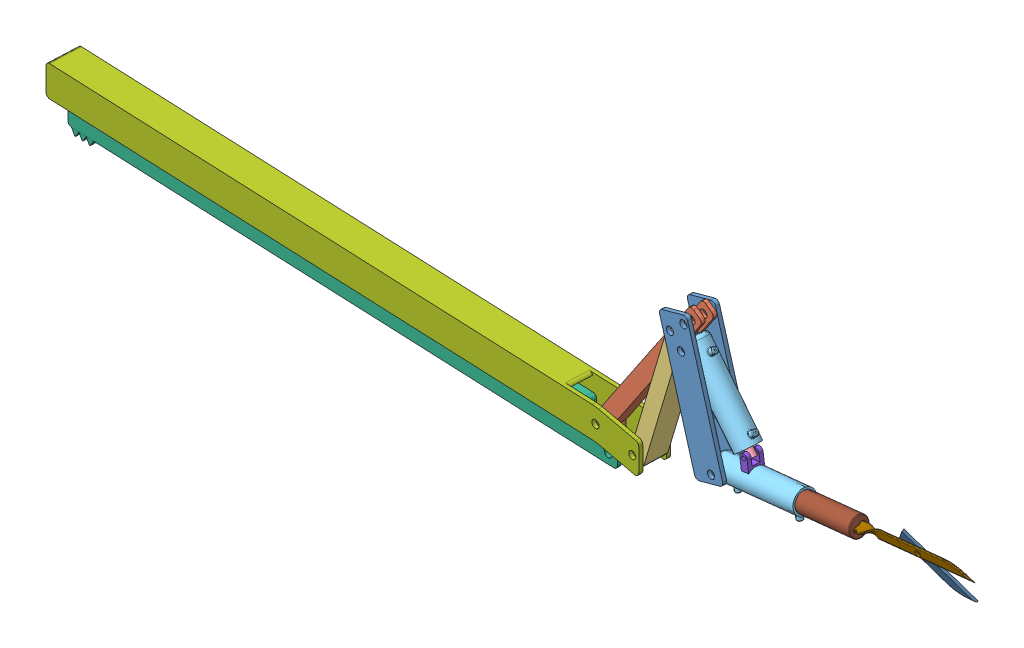
SolidWorks assembly robot arm, configuration Default. Lengths in mm.
Overall size (249.31 49.18 17.02).
13 component instances, 11 part files, 32 mates.
Components (placement in the parent):
- bottom arm-1: bottom arm [Default] at (-76.3272 70.555 28.6801) x (0.289518 -0.957095 0.01218) z (-0.042034 0 0.999116) size (35 8 8)
- mid arm1-1: mid arm1 [Default] at (-97.3359 34.2899 27.7962) x (-0.564195 -0.8253 -0.023736) z (0.042034 0 -0.999116) size (52.07 8.95 4)
- mid arm2-1: mid arm2 [Default] at (-87.409 30.4601 28.2139) x (0.293429 0.955901 0.012345) z (-0.042034 0 0.999116) size (39 4 6)
- piston-1: piston [Default] at (-71.6815 60.1738 28.8755) x (-0.649646 0.759745 -0.027331) z (-0.042034 0 0.999116) size (21 5 5)
- pump-1: pump [Default] at (-73.0366 61.7586 28.8185) x (0.649646 -0.759745 0.027331) z (-0.042034 0 0.999116) size (23 7.5 6)
- uper arm1-1: uper arm1 [Default] at (-93.5493 29.9098 27.9555) x (-0.999116 0 -0.042034) z (-0.042034 0 0.999116) size (150 11.53 4)
- uper arm2-1: uper arm2 [Default] at (-97.3359 34.4359 27.7962) x (-0.999116 0 -0.042034) z (-0.042034 0 0.999116) size (161.82 9.89 8)
- piston-2: piston [Default] at (-57.7397 40.4075 29.4621) x (-0.989211 -0.140461 -0.041617) z (-0.134091 0.982548 -0.128913) size (21 5 5)
- pump-2: pump [Default] at (-64.3331 39.4713 29.1847) x (0.989211 0.140461 0.041617) z (0.042034 0 -0.999116) size (23 7.5 6)
- fix plate-1: fix plate [Default] at (-58.838 44.0131 27.4141) x (0.989211 0.140461 0.041617) z (-0.042034 0 0.999116) size (2 9.44 6)
- sissors1-1: sissors1 [Default] at (-33.0095 43.919 30.5025) x (0.146102 -0.966743 -0.209912) z (-0.010748 -0.213728 0.976834) size (4.54 40 4.53)
- sissors2-1: sissors2 [Default] at (-17.9664 48.965 31.2602) x (-0.427031 -0.882348 -0.197753) z (0.904173 -0.419264 -0.081784) size (2.92 0.5 19.68)
- twist-1: twist [Default] at (-29.7107 44.3874 30.6413) x (-0.003755 0.308298 -0.951282) z (-0.146448 0.940863 0.3055) size (5 15 5)
Mates (geometry in assembly coordinates):
- 平行(R)1: parallel anti-aligned: plane of uper arm2-1 through (-247.3294 37.2899 24.4885) normal (0 -1 0); plane of assembly through (0 0 0) normal (0 1 0)
- 平行(R)2: parallel anti-aligned: plane of uper arm1-1 through (-243.5008 34.9098 23.6487) normal (0 1 0); plane of uper arm2-1 through (-247.3294 37.2899 24.4885) normal (0 -1 0)
- 重合/共線/共點11: coincident anti-aligned: plane of mid arm2-1 through (-74.1813 67.1529 31.773) normal (-0.042034 0 0.999116); plane of uper arm2-1 through (-247.3294 30.2899 24.4885) normal (0.042034 0 -0.999116)
- 重合/共線/共點12: coincident anti-aligned: plane of mid arm2-1 through (-77.9595 68.3276 30.6132) normal (0.042034 0 -0.999116); plane of uper arm1-1 through (-243.5008 34.9098 23.6487) normal (-0.042034 0 0.999116)
- 同軸心6: concentric anti-aligned: cylinder of mid arm2-1 through (-87.4258 32.5187 31.2158) axis (0.042034 0 -0.999116) radius 1; cylinder of uper arm2-1 through (-87.1316 32.5187 24.222) axis (-0.042034 0 0.999116) radius 0.9659
- 同軸心7: concentric anti-aligned: cylinder of mid arm1-1 through (-96.2572 27.4098 32.846) axis (0.042034 0 -0.999116) radius 1; cylinder of uper arm1-1 through (-95.963 27.4098 25.8522) axis (-0.042034 0 0.999116) radius 1
- 同軸心8: concentric anti-aligned: cylinder of mid arm1-1 through (-97.546 34.2899 32.7918) axis (0.042034 0 -0.999116) radius 1; cylinder of uper arm2-1 through (-97.1677 34.2899 23.7998) axis (-0.042034 0 0.999116) radius 1
- 重合/共線/共點13: coincident anti-aligned: plane of mid arm1-1 through (-96.005 27.4098 26.8513) normal (0.042034 0 -0.999116); plane of uper arm1-1 through (-243.3747 33.9098 20.6514) normal (-0.042034 0 0.999116)
- 同軸心9: concentric aligned: cylinder of bottom arm-1 through (-73.5257 69.3652 32.8015) axis (0.042034 0 -0.999116) radius 1; cylinder of mid arm1-1 through (-73.4416 69.3652 30.8033) axis (0.042034 0 -0.999116) radius 1
- 重合/共線/共點14: coincident anti-aligned: plane of bottom arm-1 through (-62.4952 38.2157 32.2647) normal (0.042034 0 -0.999116); plane of mid arm2-1 through (-74.1813 67.1529 31.773) normal (-0.042034 0 0.999116)
- 同軸心11: concentric aligned: cylinder of bottom arm-1 through (-77.1978 65.9753 32.647) axis (0.042034 0 -0.999116) radius 1; cylinder of mid arm2-1 through (-77.1558 65.9753 31.6479) axis (0.042034 0 -0.999116) radius 1
- 同軸心12: concentric aligned: cylinder of bottom arm-1 through (-77.1978 65.9753 32.647) axis (0.042034 0 -0.999116) radius 1; cylinder of mid arm2-1 through (-77.1558 65.9753 31.6479) axis (0.042034 0 -0.999116) radius 1
- 同軸心13: concentric aligned: cylinder of bottom arm-1 through (-77.1978 65.9753 32.647) axis (0.042034 0 -0.999116) radius 1; cylinder of mid arm2-1 through (-77.1558 65.9753 31.6479) axis (0.042034 0 -0.999116) radius 1
- 同軸心14: concentric aligned: cylinder of bottom arm-1 through (-77.1978 65.9753 32.647) axis (0.042034 0 -0.999116) radius 1; cylinder of mid arm2-1 through (-77.1558 65.9753 31.6479) axis (0.042034 0 -0.999116) radius 1
- 同軸心15: concentric aligned: cylinder of bottom arm-1 through (-77.1978 65.9753 32.647) axis (0.042034 0 -0.999116) radius 1; cylinder of mid arm2-1 through (-77.1558 65.9753 31.6479) axis (0.042034 0 -0.999116) radius 1
- 同軸心16: concentric anti-aligned: cylinder of piston-1 through (-72.3311 60.9335 28.8482) axis (0.649646 -0.759745 0.027331) radius 2.5; cylinder of pump-1 through (-60.0437 46.5637 29.3651) axis (-0.649646 0.759745 -0.027331) radius 2.5
- 相切(T)1: tangent anti-aligned: plane of bottom arm-1 through (-62.4952 38.2157 32.2647) normal (0.042034 0 -0.999116); cylinder of pump-1 through (-60.0437 46.5637 29.3651) axis (-0.649646 0.759745 -0.027331) radius 3
- 同軸心17: concentric anti-aligned: cylinder of bottom arm-1 through (-74.1792 62.8982 32.774) axis (0.042034 0 -0.999116) radius 1; cylinder of pump-1 through (-73.885 62.8982 25.7802) axis (-0.042034 0 0.999116) radius 1
- 同軸心19: concentric anti-aligned: cylinder of piston-2 through (-58.7289 40.267 29.4205) axis (0.989211 0.140461 0.041617) radius 2.5; cylinder of pump-2 through (-44.5488 42.2805 30.017) axis (-0.989211 -0.140461 -0.041617) radius 2.5
- 相切(T)3: tangent anti-aligned: plane of bottom arm-1 through (-68.9367 36.1873 25.9884) normal (-0.042034 0 0.999116); cylinder of pump-2 through (-44.5488 42.2805 30.017) axis (-0.989211 -0.140461 -0.041617) radius 3
- 同軸心20: concentric anti-aligned: cylinder of pump-2 through (-44.5488 42.2805 30.017) axis (-0.989211 -0.140461 -0.041617) radius 3; cylinder of fix plate-1 through (-59.387 40.1736 29.3928) axis (0.989211 0.140461 0.041617) radius 3
- 平行相距1: distance = 8 mm aligned: plane of fix plate-1 through (-59.9954 43.8726 31.3689) normal (-0.989211 -0.140461 -0.041617); plane of pump-2 through (-67.3007 39.0499 29.0598) normal (-0.989211 -0.140461 -0.041617)
- 同軸心21: concentric anti-aligned: cylinder of piston-1 through (-59.0275 45.4982 26.9057) axis (-0.042034 0 0.999116) radius 0.5; cylinder of fix plate-1 through (-59.2167 45.4982 31.4017) axis (0.042034 0 -0.999116) radius 0.5
- 同軸心23: concentric aligned: cylinder of piston-2 through (-37.9555 43.2167 30.2944) axis (-0.989211 -0.140461 -0.041617) radius 1; cylinder of sissors1-1 through (-36.9663 43.3572 30.336) axis (-0.989211 -0.140461 -0.041617) radius 0.15
- 重合/共線/共點16: coincident anti-aligned: plane of piston-2 through (-37.9555 43.2167 30.2944) normal (0.989211 0.140461 0.041617); plane of sissors1-1 through (-37.9555 43.2167 30.2944) normal (-0.989211 -0.140461 -0.041617)
- 同軸心24: concentric anti-aligned: cylinder of sissors1-1 through (-13.2643 47.4603 29.8209) axis (-0.010748 -0.213728 0.976834) radius 0.75; cylinder of sissors2-1 through (-13.2806 47.1373 31.2973) axis (0.010748 0.213728 -0.976834) radius 0.75
- 重合/共線/共點17: coincident anti-aligned: plane of sissors1-1 through (1.7768 47.7941 31.6066) normal (0.010748 0.213728 -0.976834); plane of sissors2-1 through (-0.3585 39.5248 29.7739) normal (-0.010748 -0.213728 0.976834)
- 同軸心26: concentric aligned: cylinder of bottom arm-1 through (-65.985 39.2606 33.1187) axis (0.042034 0 -0.999116) radius 1; cylinder of pump-2 through (-65.943 39.2606 32.1196) axis (0.042034 0 -0.999116) radius 1
- 同軸心27: concentric aligned: cylinder of bottom arm-1 through (-65.985 39.2606 33.1187) axis (0.042034 0 -0.999116) radius 1; cylinder of pump-2 through (-65.943 39.2606 32.1196) axis (0.042034 0 -0.999116) radius 1
- 同軸心28: concentric anti-aligned: cylinder of pump-2 through (-44.5488 42.2805 30.017) axis (-0.989211 -0.140461 -0.041617) radius 3; cylinder of twist-1 through (-44.5488 42.2805 30.017) axis (0.989211 0.140461 0.041617) radius 2.5
- 同軸心29: concentric anti-aligned: cylinder of pump-2 through (-44.5488 42.2805 30.017) axis (-0.989211 -0.140461 -0.041617) radius 3; cylinder of twist-1 through (-44.5488 42.2805 30.017) axis (0.989211 0.140461 0.041617) radius 2.5
- 重合/共線/共點19: coincident anti-aligned: plane of pump-2 through (-44.5488 42.2805 30.017) normal (0.989211 0.140461 0.041617); plane of twist-1 through (-44.5488 42.2805 30.017) normal (-0.989211 -0.140461 -0.041617)
